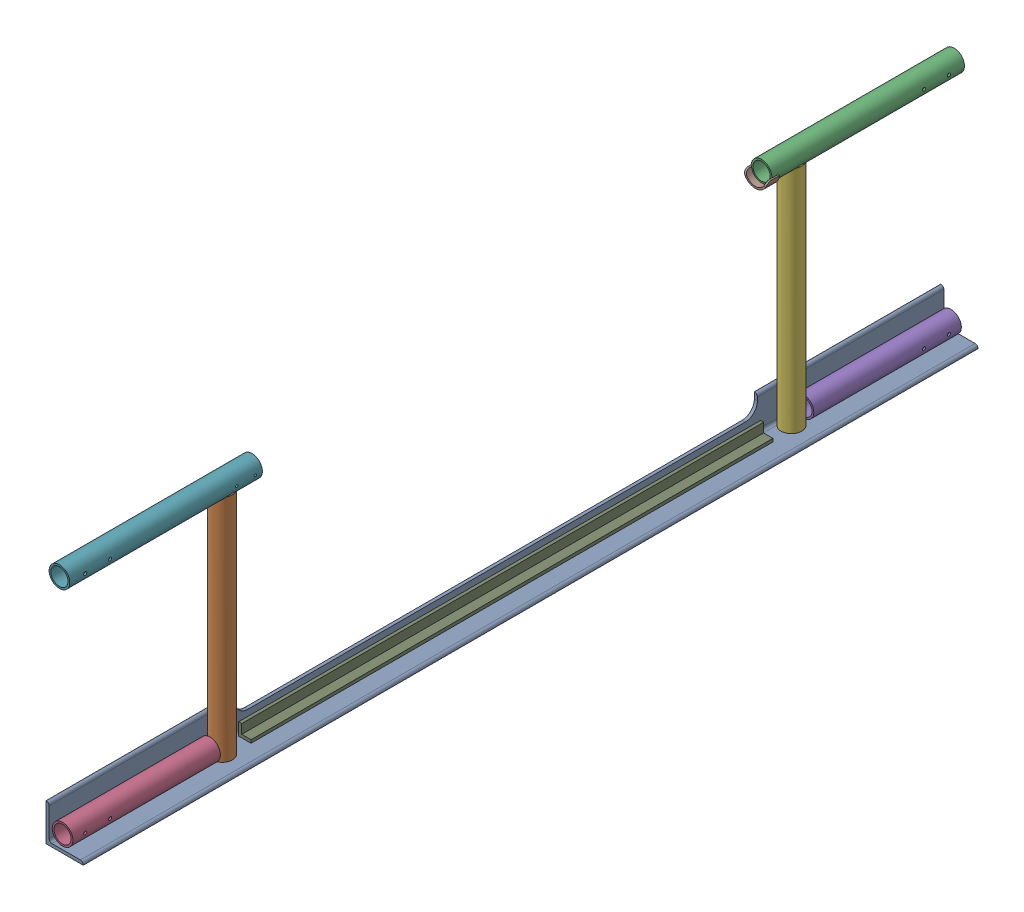
SolidWorks assembly FE-00006_ASM, configuration Default. Lengths in mm.
Overall size (76.2 507.65 1828.8).
9 component instances, 7 part files, 0 mates.
Components (placement in the parent):
- FE-00006-01-1: FE-00006-01 [Default] at origin size (76.2 76.2 1828.8)
- FE-00006-10-1: FE-00006-10 [Default] at (27.432 6.35 1496.2188) size (42.16 471.23 42.16)
- FE-00006-03-1: FE-00006-03 [Default] at (27.432 486.5688 393.7) x (1 0 0) z (0 0 -1) size (42.16 42.16 393.7)
- FE-00006-02-1: FE-00006-02 [Default] at (27.432 27.432 1520.825) size (42.16 42.16 301.62)
- FE-00006-02-2: FE-00006-02 [Default] at (27.432 27.432 307.975) x (1 0 0) z (0 0 -1) size (42.16 42.16 301.62)
- FE-00006-10-2: FE-00006-10 [Default] at (27.432 6.35 332.5876) size (42.16 471.23 42.16)
- FE-00006-05-1: FE-00006-05 [Default] at (27.432 486.5688 1435.1) size (42.16 42.16 393.7)
- FE-00006-08-1: FE-00006-08 [Default] at (27.432 486.5688 381) size (48.26 22.22 25.4)
- FE-00006-09-1: FE-00006-09 [Default] at (12.7 6.35 381) size (25.4 25.4 1066.8)
